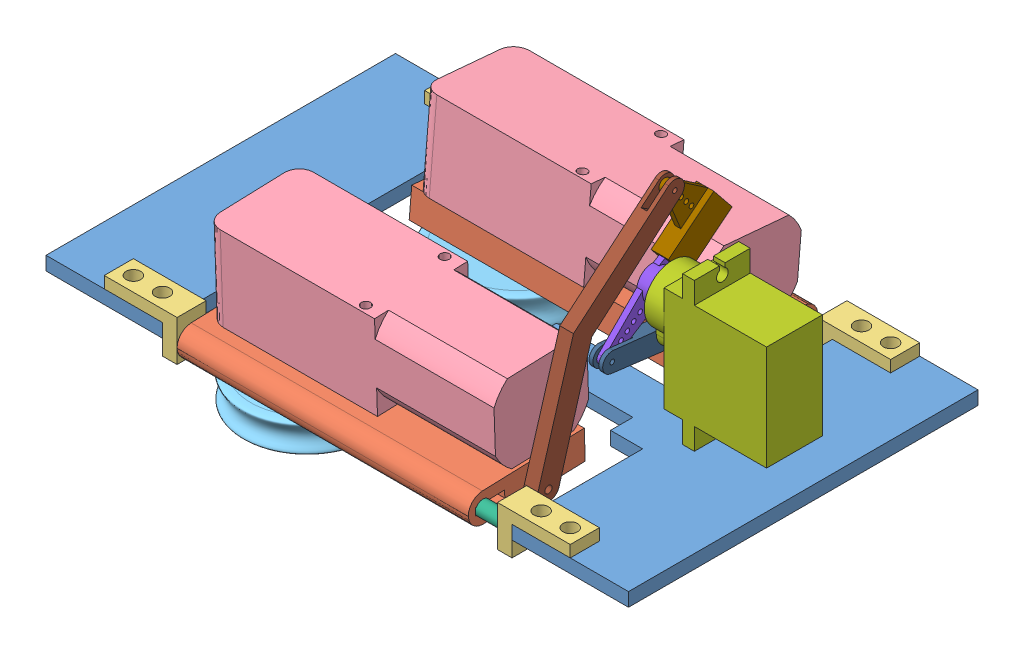
SolidWorks assembly Assembly, configuration Default. Lengths in mm.
Overall size (127 62.82 83.31).
18 component instances, 11 part files, 65 mates.
Components (placement in the parent):
- Chassis-1: Chassis [Default] at origin size (127 2.97 76.2)
- Wheel Standoff-1: Wheel Standoff [Default] at (0 -3.0475 25.2961) x (1 0 0) z (0 0.999404 0.034519) size (66.55 25.4 6.35)
- Bracket-1: Bracket [Default] at (50.8 5.5118 31.75) x (1 0 0) z (0 0 -1) size (15.88 8.89 6.35)
- Bracket-2: Bracket [Default] at (-50.8 5.5118 38.1) x (-1 0 0) z (0 0 1) size (15.88 8.89 6.35)
- TT Motor-2: TT Motor [Default] at (3.175 22.1931 22.991) x (-1 0 0) z (0 -0.999404 -0.034519) size (62.74 20.32 27.18)
- Wheel-1: Wheel [Default] at (-22.225 -8.6495 21.9257) x (0 0.999404 0.034519) z (-0.974079 0.007809 -0.226075) size (15.24 31.75 31.75)
- Bracket-3: Bracket [Default] at (50.8 5.5118 -38.1) x (1 0 0) z (0 0 -1) size (15.88 8.89 6.35)
- Bracket-4: Bracket [Default] at (-50.8 5.5118 -31.75) x (-1 0 0) z (0 0 1) size (15.88 8.89 6.35)
- Wheel Standoff-2: Wheel Standoff [Default] at (0 3.7993 -25.7171) x (1 0 0) z (0 -0.996105 0.088177) size (66.55 25.4 6.35)
- TT Motor-3: TT Motor [Default] at (3.175 22.8021 -24.2118) x (-1 0 0) z (0 -0.996105 0.088177) size (62.74 20.32 27.18)
- Wheel-2: Wheel [Default] at (-22.225 -7.9387 -21.4906) x (0 0.996105 -0.088177) z (0.259456 -0.085157 -0.961993) size (15.24 31.75 31.75)
- .125 rod-1: .125 rod [Default] at (-38.1 -0.2032 34.925) x (0 0.375473 -0.926833) z (0 -0.926833 -0.375473) size (3.17 76.2 3.17)
- .125 rod-2: .125 rod [Default] at (-38.1 -0.2032 -34.925) x (0 -1 0) z (0 0 1) size (3.17 76.2 3.17)
- Servo-1: Servo [Default] at (61.595 20.7518 0) x (0 -1 0) z (0 0 -1) size (32.26 29.72 12.19)
- Servo Double Arm-1: Servo Double Arm [Default] at (34.163 26.0858 0) x (0 0.778248 0.627958) z (0 -0.627958 0.778248) size (6.86 3.56 30.48)
- Servo Double Arm Adapter-1: Servo Double Arm Adapter [Default] at (34.163 26.0858 0) x (0 0.778248 0.627958) z (0 -0.627958 0.778248) size (16.15 3.81 19.94)
- Linkage Right-2: Linkage Right [Default] at (32.7279 17.3132 10.8721) x (0 0.423037 0.906112) z (-1 0 0) size (43.85 11.36 2.97)
- Linkage-3: Linkage [Default] at (29.7561 42.8574 -2.7859) x (0 0.840066 -0.542484) z (1 0 0) size (55.28 12.3 2.97)
Mates (geometry in assembly coordinates):
- Concentric2: concentric aligned: cylinder of Adapter-1 through (16.2909 38.4849 39.8981) axis (0 1 0) radius 1.5875; cylinder of Chassis-1 through (41.6909 35.5131 39.8981) axis (0 1 0) radius 1.5875
- Concentric3: concentric aligned: cylinder of Adapter-1 through (41.6909 38.4849 39.8981) axis (0 1 0) radius 1.5875; cylinder of Chassis-1 through (41.275 0 34.925) axis (0 1 0) radius 1.5875
- Coincident1: coincident anti-aligned: plane of Adapter-1 through (28.9909 38.4849 39.8981) normal (0 -1 0); plane of Chassis-1 through (0 2.9718 0) normal (0 1 0)
- Concentric4: concentric aligned: cylinder of Adapter-1 through (13.1159 35.3099 39.8981) axis (1 0 0) radius 1.5875; cylinder of Wheel Standoff-1 through (-34.925 -0.2032 34.925) axis (1 0 0) radius 1.5875
- Coincident2: coincident anti-aligned: plane of Adapter-1 through (25.8159 32.1349 36.7231) normal (-1 0 0); plane of Wheel Standoff-1 through (54.3909 25.7283 42.8978) normal (1 0 0)
- Coincident3: coincident anti-aligned: plane of Chassis-1 through (0 2.9718 0) normal (0 1 0); plane of Bracket-1 through (50.8 2.9718 31.75) normal (0 -1 0)
- Concentric7: concentric aligned: cylinder of Wheel Standoff-1 through (-34.925 -0.2032 34.925) axis (1 0 0) radius 1.5875; cylinder of Bracket-1 through (34.925 -0.2032 34.925) axis (1 0 0) radius 1.5875
- Coincident4: coincident anti-aligned: plane of Wheel Standoff-1 through (-34.925 3.2987 25.5153) normal (-1 0 0); plane of Bracket-2 through (-34.925 5.5118 38.1) normal (1 0 0)
- Concentric8: concentric anti-aligned: cylinder of Wheel Standoff-1 through (-22.225 3.4083 22.3422) axis (0 -0.999404 -0.034519) radius 4.7625; cylinder of TT Motor-1 through (57.5659 25.6844 34.8794) axis (0 0.830995 -0.556281) radius 2.54
- Coincident5: coincident anti-aligned: plane of Wheel Standoff-1 through (28.9909 38.6193 30.4189) normal (0 0.9999 0.014136); plane of TT Motor-1
- Concentric9: concentric aligned: cylinder of Chassis-1 through (47.625 0 34.925) axis (0 1 0) radius 1.5875; cylinder of Bracket-1 through (47.625 2.9718 34.925) axis (0 1 0) radius 1.5875
- Concentric10: concentric aligned: cylinder of Chassis-1 through (41.275 0 34.925) axis (0 1 0) radius 1.5875; cylinder of Bracket-1 through (41.275 2.9718 34.925) axis (0 1 0) radius 1.5875
- Concentric11: concentric aligned: cylinder of Chassis-1 through (-41.275 0 34.925) axis (0 1 0) radius 1.5875; cylinder of Bracket-2 through (-41.275 2.9718 34.925) axis (0 1 0) radius 1.5875
- Concentric12: concentric aligned: cylinder of Chassis-1 through (-47.625 0 34.925) axis (0 1 0) radius 1.5875; cylinder of Bracket-2 through (-47.625 2.9718 34.925) axis (0 1 0) radius 1.5875
- Coincident8: coincident anti-aligned: plane of Chassis-1 through (0 2.9718 0) normal (0 1 0); plane of Bracket-2 through (-50.8 2.9718 38.1) normal (0 -1 0)
- Concentric13: concentric anti-aligned: cylinder of Wheel Standoff-2 through (-34.925 -0.2032 -34.925) axis (1 0 0) radius 1.5875; cylinder of Bracket-4 through (-34.925 -0.2032 -34.925) axis (-1 0 0) radius 1.5875
- Concentric14: concentric anti-aligned: cylinder of Wheel Standoff-1 through (-22.225 3.4083 22.3422) axis (0 -0.999404 -0.034519) radius 4.7625; cylinder of Linker-1 through (28.9909 38.3603 30.3324) axis (0 0.999915 -0.013054) radius 2.3813
- Concentric15: concentric anti-aligned: cylinder of Wheel Standoff-1 through (28.9909 38.2567 22.3956) axis (0 -0.999915 0.013054) radius 2.3813; cylinder of Linker-1 through (28.9909 38.2567 22.3956) axis (0 0.999915 -0.013054) radius 2.3813
- Coincident11: coincident anti-aligned: plane of Wheel Standoff-1 through (28.9909 38.6193 30.4189) normal (0 0.9999 0.014136); plane of Linker-1 through (0.4159 38.3085 26.364) normal (0 -0.999915 0.013054)
- Concentric16: concentric anti-aligned: cylinder of Linker-1 through (16.2909 41.2801 26.3252) axis (0 -0.999915 0.013054) radius 4.7625; cylinder of TT Motor-2 through (-22.225 -4.9687 22.0528) axis (0 0.999404 0.034519) radius 2.54
- Coincident12: coincident anti-aligned: plane of Linker-1 through (0.4159 41.2801 26.3252) normal (0 0.999915 -0.013054); plane of TT Motor-2 through (3.175 3.4083 22.3422) normal (0 -0.999404 -0.034519)
- Concentric17: concentric anti-aligned: cylinder of Wheel Standoff-1 through (-22.225 3.4083 22.3422) axis (0 -0.999404 -0.034519) radius 4.7625; cylinder of TT Motor-2 through (-22.225 -4.9687 22.0528) axis (0 0.999404 0.034519) radius 2.54
- Coincident13: coincident anti-aligned: plane of Wheel Standoff-1 through (0 3.2987 25.5153) normal (0 0.999404 0.034519); plane of TT Motor-2 through (3.175 3.4083 22.3422) normal (0 -0.999404 -0.034519)
- Parallel4: parallel aligned: plane of Wheel Standoff-1 through (-34.925 3.2987 25.5153) normal (-1 0 0); plane of TT Motor-2 through (-33.655 3.0576 32.4961) normal (-1 0 0)
- Concentric18: concentric aligned: cylinder of Wheel Standoff-1 through (-22.225 3.4083 22.3422) axis (0 -0.999404 -0.034519) radius 4.7625; cylinder of Wheel-1 through (-22.225 3.4083 22.3422) axis (0 -0.999404 -0.034519) radius 4.7625
- Coincident14: coincident anti-aligned: plane of TT Motor-2 through (3.175 3.4083 22.3422) normal (0 -0.999404 -0.034519); plane of Wheel-1 through (-22.225 3.4083 22.3422) normal (0 0.999404 0.034519)
- Concentric19: concentric aligned: cylinder of Chassis-1 through (47.625 0 -34.925) axis (0 1 0) radius 1.5875; cylinder of Bracket-3 through (47.625 2.9718 -34.925) axis (0 1 0) radius 1.5875
- Concentric20: concentric aligned: cylinder of Chassis-1 through (41.275 0 -34.925) axis (0 1 0) radius 1.5875; cylinder of Bracket-3 through (41.275 2.9718 -34.925) axis (0 1 0) radius 1.5875
- Coincident15: coincident anti-aligned: plane of Chassis-1 through (0 2.9718 0) normal (0 1 0); plane of Bracket-3 through (50.8 2.9718 -38.1) normal (0 -1 0)
- Coincident16: coincident anti-aligned: plane of Chassis-1 through (0 2.9718 0) normal (0 1 0); plane of Bracket-4 through (-50.8 2.9718 -31.75) normal (0 -1 0)
- Concentric21: concentric aligned: cylinder of Chassis-1 through (-41.275 0 -34.925) axis (0 1 0) radius 1.5875; cylinder of Bracket-4 through (-41.275 2.9718 -34.925) axis (0 1 0) radius 1.5875
- Concentric22: concentric aligned: cylinder of Chassis-1 through (-47.625 0 -34.925) axis (0 1 0) radius 1.5875; cylinder of Bracket-4 through (-47.625 2.9718 -34.925) axis (0 1 0) radius 1.5875
- Coincident17: coincident anti-aligned: plane of Bracket-4 through (-34.925 5.5118 -31.75) normal (1 0 0); plane of Wheel Standoff-2 through (-34.925 -2.5259 -25.1571) normal (-1 0 0)
- Coincident18: coincident anti-aligned: plane of Wheel Standoff-2 through (0 3.7993 -25.7171) normal (0 0.996105 -0.088177); plane of TT Motor-3 through (3.175 4.0793 -22.5544) normal (0 -0.996105 0.088177)
- Concentric24: concentric aligned: cylinder of Wheel Standoff-2 through (-22.225 -2.246 -21.9945) axis (0 0.996105 -0.088177) radius 4.7625; cylinder of TT Motor-3 through (-22.225 -4.2701 -21.8153) axis (0 0.996105 -0.088177) radius 2.54
- Parallel6: parallel aligned: plane of Wheel Standoff-2 through (-34.925 -2.5259 -25.1571) normal (-1 0 0); plane of TT Motor-3 through (-33.655 4.9752 -12.434) normal (-1 0 0)
- Coincident20: coincident anti-aligned: plane of TT Motor-3 through (3.175 4.0793 -22.5544) normal (0 -0.996105 0.088177); plane of Wheel-2 through (-22.225 4.0793 -22.5544) normal (0 0.996105 -0.088177)
- Concentric25: concentric anti-aligned: cylinder of Wheel Standoff-2 through (-22.225 -2.246 -21.9945) axis (0 0.996105 -0.088177) radius 4.7625; cylinder of Wheel-2 through (-22.225 4.0793 -22.5544) axis (0 -0.996105 0.088177) radius 4.7625
- Concentric26: concentric anti-aligned: cylinder of Wheel Standoff-1 through (-34.925 -0.2032 34.925) axis (1 0 0) radius 1.5875; cylinder of .125 rod-1 through (38.1 -0.2032 34.925) axis (-1 0 0) radius 1.5875
- Coincident21: coincident aligned: plane of Bracket-1 through (38.1 5.5118 31.75) normal (1 0 0); plane of .125 rod-1 through (38.1 -0.2032 34.925) normal (1 0 0)
- Concentric28: concentric anti-aligned: cylinder of Wheel Standoff-2 through (-34.925 -0.2032 -34.925) axis (1 0 0) radius 1.5875; cylinder of .125 rod-2 through (38.1 -0.2032 -34.925) axis (-1 0 0) radius 1.5875
- Coincident22: coincident aligned: plane of Bracket-3 through (38.1 5.5118 -38.1) normal (1 0 0); plane of .125 rod-2 through (38.1 -0.2032 -34.925) normal (1 0 0)
- Coincident25: coincident aligned: plane of Bracket-1 through (34.925 5.5118 31.75) normal (-1 0 0); plane of Servo-1 through (34.925 26.0858 0) normal (-1 0 0)
- Concentric29: concentric aligned: cylinder of Servo-1 through (31.877 26.0858 0) axis (1 0 0) radius 2.413; cylinder of Servo Double Arm-1 through (30.607 26.0858 0) axis (1 0 0) radius 2.286
- Coincident26: coincident anti-aligned: plane of Servo-1 through (31.877 26.0858 0) normal (-1 0 0); plane of Servo Double Arm-1 through (31.877 26.0858 0) normal (1 0 0)
- Coincident27: coincident aligned: plane of Chassis-1 through (0 0 0) normal (0 0 1)
- Coincident28: coincident aligned: plane of Chassis-1 through (0 0 0) normal (0 1 0)
- Coincident29: coincident aligned: plane of Chassis-1 through (0 0 0) normal (1 0 0)
- Concentric31: concentric anti-aligned: cylinder of Wheel Standoff-1 through (31.623 0.182 24.7722) axis (-1 0 0) radius 0.7937; cylinder of Linkage-1 through (29.7561 5.0081 23.3434) axis (1 0 0) radius 0.7937
- Distance5: distance = 6.35 mm anti-aligned: plane of Chassis-1 through (0 2.9718 0) normal (0 1 0); plane of Servo-1 through (39.243 9.3218 -6.096) normal (0 -1 0)
- Distance4: distance = 6.096 mm anti-aligned: plane of Servo-1 through (39.243 32.1818 -6.096) normal (0 0 -1); plane of Chassis-1 through (0 0 0) normal (0 0 1)
- Coincident42: coincident anti-aligned: plane of Servo Double Arm-1 through (30.607 26.0858 0) normal (-1 0 0); plane of Linkage-2 through (30.607 34.3558 4.9567) normal (1 0 0)
- Concentric32: concentric aligned: cylinder of Servo Double Arm-1 through (34.163 34.8584 -10.8721) axis (-1 0 0) radius 0.508; cylinder of Linkage-2 through (32.7279 39.2266 4.7412) axis (-1 0 0) radius 0.508
- Concentric33: concentric aligned: cylinder of Wheel Standoff-1 through (31.623 0.182 24.7722) axis (-1 0 0) radius 0.7937; cylinder of Linkage-2 through (32.7279 4.7822 26.0722) axis (-1 0 0) radius 0.7937
- Concentric35: concentric anti-aligned: cylinder of Wheel Standoff-2 through (31.623 0.6583 -24.8015) axis (-1 0 0) radius 0.7937; cylinder of Linkage Right-1 through (31.0485 0.8578 -24.8205) axis (1 0 0) radius 0.7937
- Concentric36: concentric anti-aligned: cylinder of Linkage Right-1 through (31.0485 13.0855 -5.1139) axis (1 0 0) radius 0.508; cylinder of Servo Double Arm-1 through (34.163 17.3132 10.8721) axis (-1 0 0) radius 0.508
- Concentric37: concentric aligned: cylinder of Servo Double Arm-1 through (31.877 34.8697 -10.8862) axis (-1 0 0) radius 1.252; cylinder of Servo Double Arm Adapter-1 through (31.877 34.8697 -10.8862) axis (-1 0 0) radius 1.252
- Coincident46: coincident anti-aligned: plane of Servo Double Arm-1 through (31.877 24.1283 -1.9681) normal (0 -0.705205 -0.709003); plane of Servo Double Arm Adapter-1 through (31.877 24.1283 -1.9681) normal (0 0.705205 0.709003)
- Coincident47: coincident anti-aligned: plane of Servo Double Arm-1 through (31.877 26.0858 0) normal (1 0 0); plane of Servo Double Arm Adapter-1 through (31.877 26.0858 0) normal (-1 0 0)
- Concentric38: concentric anti-aligned: cylinder of Wheel Standoff-2 through (31.623 0.6583 -24.8015) axis (-1 0 0) radius 0.7937; cylinder of Linkage Right-2 through (29.7561 0.6583 -24.8015) axis (1 0 0) radius 0.7937
- Concentric39: concentric anti-aligned: cylinder of Servo Double Arm-1 through (34.163 17.3132 10.8721) axis (-1 0 0) radius 0.508; cylinder of Linkage Right-2 through (29.7561 17.3132 10.8721) axis (1 0 0) radius 0.508
- Concentric40: concentric anti-aligned: cylinder of Servo Double Arm Adapter-1 through (7.7117 42.8574 -2.7859) axis (1 0 0) radius 0.508; cylinder of Linkage-3 through (32.7279 42.8574 -2.7859) axis (-1 0 0) radius 0.508
- Concentric43: concentric aligned: cylinder of Wheel Standoff-1 through (31.623 0.182 24.7722) axis (-1 0 0) radius 0.7937; cylinder of Linkage-3 through (32.7279 0.182 24.7722) axis (-1 0 0) radius 0.7937
- Coincident49: coincident anti-aligned: plane of Servo Double Arm Adapter-1 through (31.877 26.0858 0) normal (1 0 0); plane of Linkage-3 through (31.877 37.9915 -2.4783) normal (-1 0 0)
- Coincident50: coincident anti-aligned: plane of Servo Double Arm-1 through (30.607 26.0858 0) normal (-1 0 0); plane of Linkage Right-2 through (30.607 13.3557 8.0244) normal (1 0 0)
